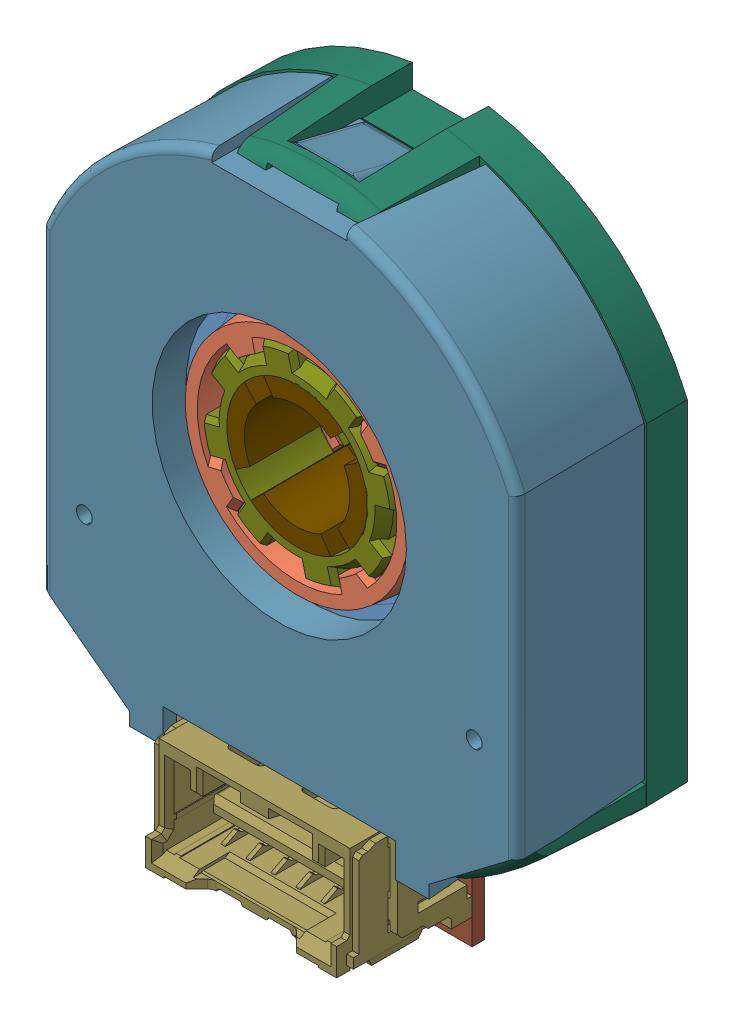
SolidWorks assembly CUI_DEVICES_cui_devices_amt223b-6350-s, configuration Default. Lengths in mm.
Overall size (28.59 39.54 12.6).
20 component instances, 18 part files, 0 mates.
Components (placement in the parent):
- CUI_DEVICES_overmold_rev_a-1: CUI_DEVICES_overmold_rev_a [Default] at (2.4928 -19.3128 13.7932) x (0.994004 -0.10934 0) z (0 0 1) size (25.6 25.6 6.65)
  - CUI_DEVICES_rotor_16f_5c_rev_d-1: CUI_DEVICES_rotor_16f_5c_rev_d [Default] at (-4.5895 18.9245 -10.5857) size (25.6 25.6 0.31)
  - CUI_DEVICES_amt-overmold_hub-rev_a-1: CUI_DEVICES_amt-overmold_hub-rev_a [Default] at (-4.5895 18.9245 -10.5807) x (-0.941518 -0.336962 0) z (0 0 1) size (14.07 14.07 6.65)
- CUI_DEVICES_amt22_asm partial(223)-1: CUI_DEVICES_amt22_asm partial(223) [Default] at (50.8 -50.8 2.53) x (-1 0 0) z (0 0 -1) size (26.62 36.93 9.56)
  - CUI_DEVICES_ecad_sot-963-1-1: CUI_DEVICES_ecad_sot-963-1 [Default] at origin size (1.12 1.02 0.41)
  - CUI_DEVICES_ecad_sot-363-1-1: CUI_DEVICES_ecad_sot-363-1 [Default] at origin size (2.9 2.49 1.09)
  - CUI_DEVICES_ecad_resonator-1-1: CUI_DEVICES_ecad_resonator-1 [Default] at origin size (3.47 2.44 1.02)
  - CUI_DEVICES_ecad_cc0603c-1-1: CUI_DEVICES_ecad_cc0603c-1 [Default] at origin size (1.47 2.69 0.76)
  - CUI_DEVICES_ecad_vson-8p-1-1: CUI_DEVICES_ecad_vson-8p-1 [Default] at origin size (3.3 3.04 0.81)
  - CUI_DEVICES_ecad_qfn21p4x4-1-1: CUI_DEVICES_ecad_qfn21p4x4-1 [Default] at origin size (4.01 4.01 1.02)
  - CUI_DEVICES_ecad_sot-23-5c-1-1: CUI_DEVICES_ecad_sot-23-5c-1 [Default] at origin size (3.81 1.78 1.27)
  - CUI_DEVICES_ecad_qfn24-1-1: CUI_DEVICES_ecad_qfn24-1 [Default] at origin size (4 4 1.52)
  - CUI_DEVICES_amt21r2-1-1: CUI_DEVICES_amt21r2-1 [Default] at origin size (26.62 36.93 0.73)
  - CUI_DEVICES_5025840660-1-1: CUI_DEVICES_5025840660-1 [Default] at origin size (13.3 7.4 7.3)
  - CUI_DEVICES_ssss810701(default)-1: CUI_DEVICES_ssss810701(default) [Default] at (50.8 30.3478 0.7315) x (1 0 0) z (0 -1 0) size (6.7 1.4 4.1)
- CUI_DEVICES_amt-203_303-top-cover_rev_h-1: CUI_DEVICES_amt-203_303-top-cover_rev_h [Default] at (0 0 6.23) x (-1 0 0) z (0 0 -1) size (28.58 32.71 7.83)
- CUI_DEVICES_amt-103-base-rev-k(default)-1: CUI_DEVICES_amt-103-base-rev-k(default) [Default] x (-1 0 0) z (0 0 -1) size (28.59 34.62 9.11)
- CUI_DEVICES_amt-shaft-adaptor-revd_fixed-1: CUI_DEVICES_amt-shaft-adaptor-revd_fixed [Default] at (0 0 1.2125) x (0.970396 0.24152 0) z (0 0 1) size (11.8 11.8 7.8)
- CUI_DEVICES_receiver-board-1: CUI_DEVICES_receiver-board [Default] at (72.2834 -20.351 4.19) x (-1 0 0) z (0 0 -1) size (26.5 26.62 0.41)
- CUI_DEVICES_amt-sleeve-rev-d(d)-1: CUI_DEVICES_amt-sleeve-rev-d(d) [Default] at (0 0 -1.3375) x (0.994004 -0.10934 0) z (0 0 1) size (10.79 10.79 7.8)
